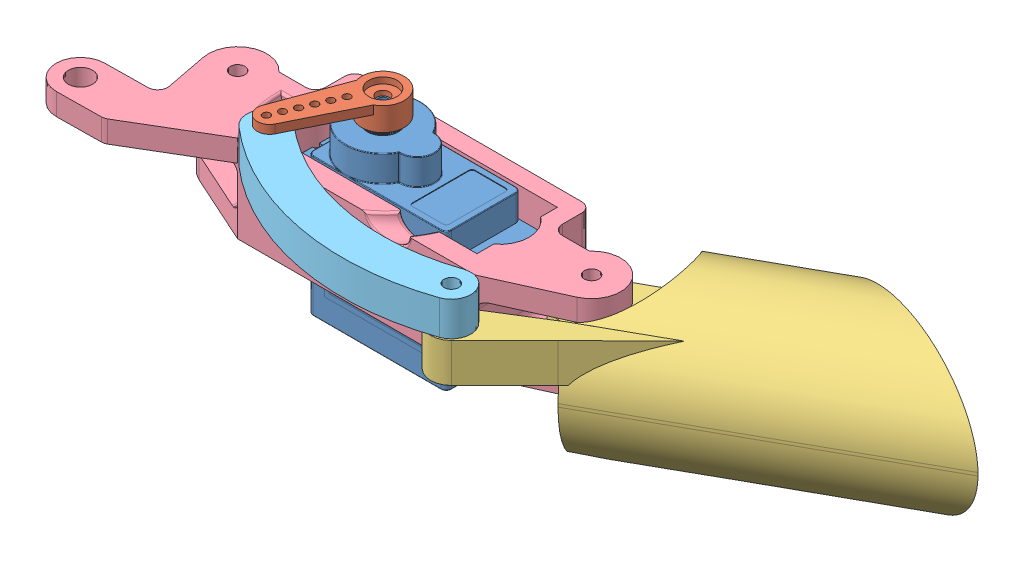
SolidWorks assembly ProximalPhalangeAssem, configuration Default. Lengths in mm.
Overall size (127.82 31.75 65.87).
6 component instances, 5 part files, 9 mates.
Components (placement in the parent):
- SG90 - Micro Servo Assembly-1: SG90 - Micro Servo Assembly [Default] at (4.8971 14.1291 22.7262) size (37.46 31.75 14.96) (flexible)
  - SG90 - Micro Servo 9g - Tower Pro.1-2: SG90 - Micro Servo 9g - Tower Pro.1 [Peça] at origin size (32.1 29.95 12.4)
  - SG90 - Micro Servo 9g - Tower Pro.2-2: SG90 - Micro Servo 9g - Tower Pro.2 [Peça] at (-5.15 21.1 0) x (0.395608 0 -0.91842) z (0.91842 0 0.395608) size (19.5 3.8 6.9)
- phalange2-1: phalange2 [Défaut] at (28.0059 19.0073 30.509) x (0 -1 0) z (-0.873423 0 0.486962) size (29.59 28.89 66.57)
- SG90 - Servo Socket-1: SG90 - Servo Socket [Default] at (-14.194 26.1193 32.4496) x (1 0 0) z (0 1 0) size (78.25 27.25 14.52)
- Bras de levier-1: Bras de levier [Default] at (19.023 28.2411 7.24) x (0 1 0) z (0.325679 0 0.94548) size (5.59 39.35 25.4)
Mates (geometry in assembly coordinates):
- Parallel1: parallel anti-aligned: plane of SG90 - Micro Servo Assembly-1/SG90 - Micro Servo 9g - Tower Pro.1-2 through (-10.3029 21.7791 28.8262) normal (0 0 1); plane of SG90 - Servo Socket-1 through (-6.7169 11.8953 29.2746) normal (0 0 -1)
- Coincident3: coincident anti-aligned: plane of SG90 - Micro Servo Assembly-1/SG90 - Micro Servo 9g - Tower Pro.1-2 through (-10.3029 19.2791 27.9762) normal (0 -1 0); plane of SG90 - Servo Socket-1 through (-14.194 19.2791 32.4496) normal (0 1 0)
- Parallel2: parallel anti-aligned: plane of SG90 - Micro Servo Assembly-1/SG90 - Micro Servo 9g - Tower Pro.1-2 through (-6.3529 74.1738 17.4762) normal (-1 0 0); plane of SG90 - Servo Socket-1 through (-11.7969 19.2791 16.1778) normal (1 0 0)
- Concentric3: concentric aligned: circle of SG90 - Micro Servo Assembly-1/SG90 - Micro Servo 9g - Tower Pro.1-2; circle of SG90 - Servo Socket_V2-1
- Concentric4: concentric aligned: circle of phalange2-1; circle of SG90 - Servo Socket-1
- Distance2: distance = 0.381 mm anti-aligned: plane of phalange2-1 through (75.9304 22.1823 -6.3904) normal (0 1 0); plane of SG90 - Servo Socket-1 through (33.939 22.5633 22.9246) normal (0 -1 0)
- Coaxiale1: concentric anti-aligned: cylinder of SG90 - Micro Servo Assembly-1/SG90 - Micro Servo 9g - Tower Pro.2-2 through (-5.9694 35.2291 35.9974) axis (0 1 0) radius 0.6; cylinder of Bras de levier-1 through (-5.9694 33.8291 35.9974) axis (0 -1 0) radius 0.9922
- Coaxiale2: concentric anti-aligned: cylinder of phalange2-1 through (31.4314 4.192 43.2628) axis (0 1 0) radius 1.7859; cylinder of Bras de levier-1 through (31.4314 33.8291 43.2628) axis (0 -1 0) radius 1.1906
- Coïncidente1: coincident anti-aligned: plane of SG90 - Micro Servo Assembly-1/SG90 - Micro Servo 9g - Tower Pro.2-2 through (-0.2529 33.8291 22.7262) normal (0 -1 0); plane of Bras de levier-1 through (25.2272 33.8291 25.2514) normal (0 1 0)
